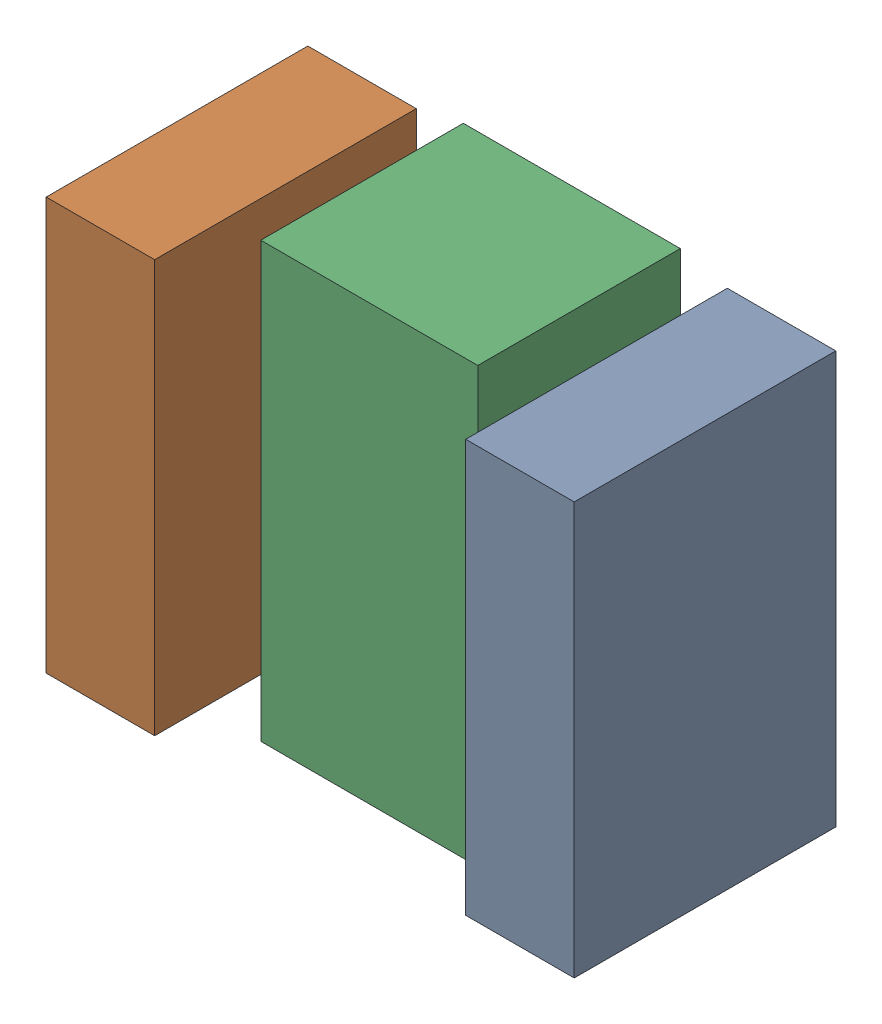
SolidWorks assembly C11_Motor_3Kanaloa_v2.0.0_Motor, configuration Default. Lengths in mm.
Overall size (3.65 3 1.81).
6 component instances, 2 part files, 0 mates.
Components (placement in the parent):
- 334788400-1: 334788400 [Default] at (36.703 81.026 0) size (0.75 2.85 1.81)
  - Extruded_5-1: Extruded_5 [Default] at origin size (0.75 2.85 1.81)
- 334788400-2: 334788400 [Default] at (33.803 81.026 0) size (0.75 2.85 1.81)
  - Extruded_5-1: Extruded_5 [Default] at origin size (0.75 2.85 1.81)
- 334788656-1: 334788656 [Default] at (35.253 81.026 0) size (1.5 3 1.4)
  - Extruded_1-1: Extruded_1 [Default] at origin size (1.5 3 1.4)
